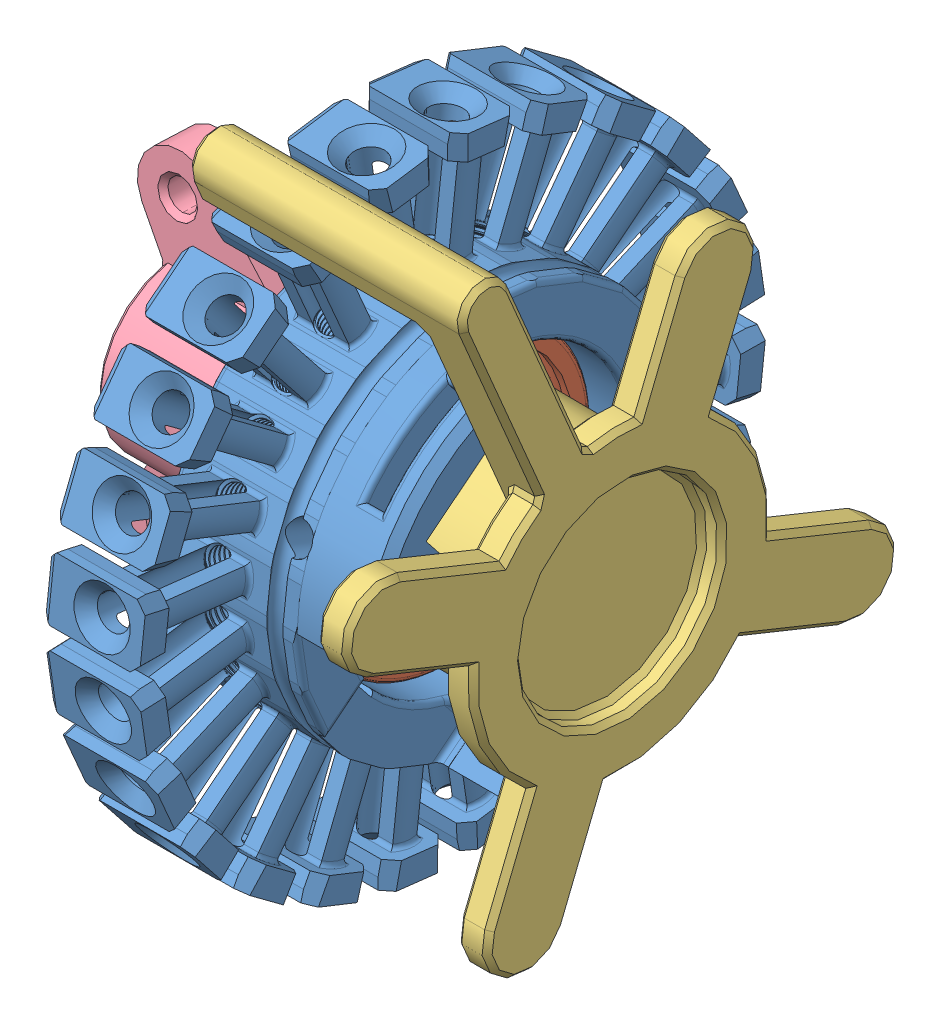
SolidWorks assembly asm_conductor, configuration По умолчанию. Lengths in mm.
Overall size (46.32 86.25 86.25).
4 component instances, 4 part files, 5 mates.
Components (placement in the parent):
- holder_var3_221003-1: holder_var3_221003 [По умолчанию] at (57.6181 39.525 38.8055) x (-1 0 0) z (0 0.783897 0.62089) size (20.23 61.4 61.4)
- skf61902-1: skf61902 [По умолчанию] at (41.3181 39.525 38.8055) size (7 28 28)
- conductor_24_09_30-1: conductor_24_09_30 [По умолчанию] at (27.8181 39.525 38.8055) x (0 -0.920394 -0.390992) z (1 0 0) size (58.18 43.36 34.69)
- screw_24_09_30-1: screw_24_09_30 [По умолчанию] at (33.7111 39.525 38.8055) x (0 0.999117 -0.042006) z (0 0.042006 0.999117) size (35.7 19.09 16.6)
Mates (geometry in assembly coordinates):
- Концентричный3: concentric aligned: cylinder of skf61902-1 through (41.3181 39.525 38.8055) axis (-1 0 0) radius 7.5; cylinder of conductor_24_09_30-1 through (44.8181 39.525 38.8055) axis (-1 0 0) radius 7.45
- Совпадение3: coincident anti-aligned: plane of skf61902-1 through (44.8181 39.525 30.5245) normal (1 0 0); plane of conductor_24_09_30-1 through (44.8181 39.525 38.8055) normal (-1 0 0)
- Концентричный4: concentric anti-aligned: cylinder of holder_var3_221003-1 through (57.6181 39.525 38.8055) axis (1 0 0) radius 14.02; cylinder of skf61902-1 through (41.3181 39.525 38.8055) axis (-1 0 0) radius 14
- Совпадение4: coincident anti-aligned: plane of holder_var3_221003-1 through (37.8181 39.525 38.8055) normal (1 0 0); plane of skf61902-1 through (37.8181 39.525 24.8055) normal (-1 0 0)
- Концентричный5: concentric anti-aligned: cylinder of conductor_24_09_30-1 through (58.8181 39.525 38.8055) axis (-1 0 0) radius 10.5; cylinder of screw_24_09_30-1 through (13.7111 39.525 38.8055) axis (1 0 0) radius 6.3
